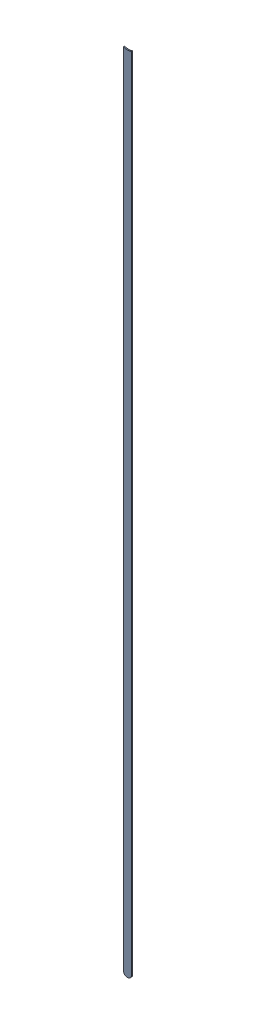
SolidWorks assembly Track (9.5mm,10.6mm)(9.5mm,35.5mm) on Top Layer, configuration Predeterminado. Lengths in mm.
Overall size (0.25 24.69 0.04).
2 component instances, 1 part files, 0 mates.
Components (placement in the parent):
- Track (9.5mm,10.6mm)(9.5mm,35.5mm) on Top Layer-1-1: Track (9.5mm,10.6mm)(9.5mm,35.5mm) on Top Layer-1 [Predeterminado] at (-68.317 -44.187 -0.0457) size (0.25 24.69 0.04)
  - Track (9.5mm,10.6mm)(9.5mm,35.5mm) on Top Layer-Part-1-1: Track (9.5mm,10.6mm)(9.5mm,35.5mm) on Top Layer-Part-1 [Predeterminado] at origin size (0.25 24.69 0.04)
